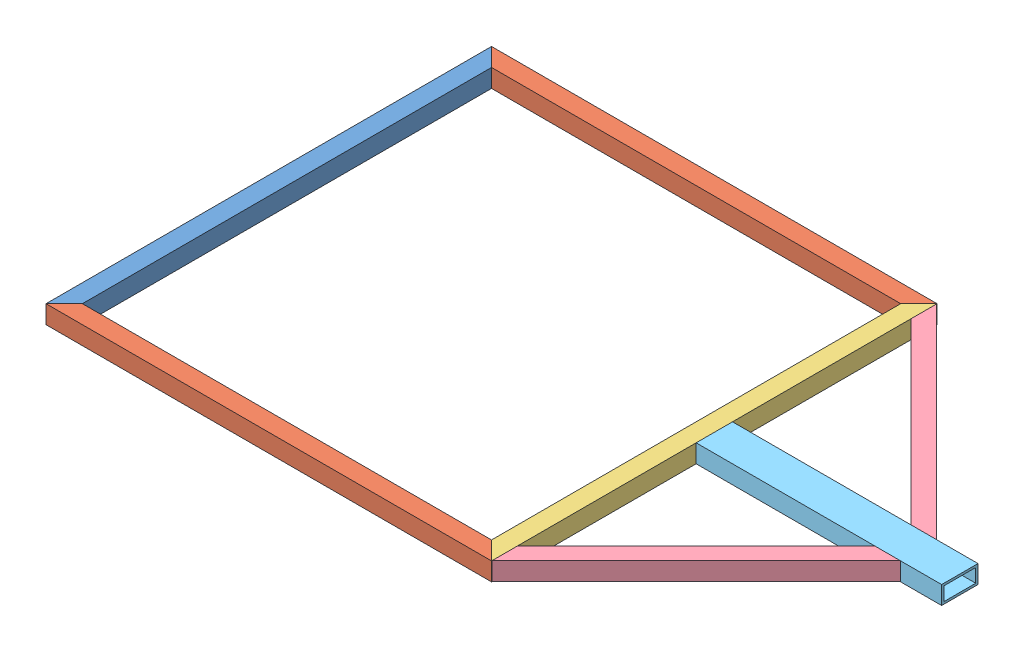
SolidWorks assembly chassis weldment top-1, configuration Default. Lengths in mm.
Overall size (965.2 25.4 622.3).
7 component instances, 5 part files, 0 mates.
Components (placement in the parent):
- frame member front-11-1: frame member front-11 [Default] at origin size (25.4 25.4 622.3)
- frame member side-11-1: frame member side-11 [Default] at (298.45 0 298.45) x (0 0 1) z (-1 0 0) size (25.4 25.4 622.3)
- frame member side-11-2: frame member side-11 [Default] at (298.45 0 -298.45) x (0 0 -1) z (-1 0 0) size (25.4 25.4 622.3)
- frame member crossbrace middle-11-1: frame member crossbrace middle-11 [Default] at (596.9 0 0) x (-1 0 0) z (0 0 1) size (25.4 25.4 622.3)
- frame member back angle-11-1: frame member back angle-11 [Default] at (743.1813 0 -158.9813) x (-0.707107 0 0.707107) z (-0.707107 0 -0.707107) size (25.4 25.4 403.23)
- frame member back angle-11-2: frame member back angle-11 [Default] at (743.1813 0 158.9813) x (-0.707107 0 -0.707107) z (-0.707107 0 0.707107) size (25.4 25.4 403.23)
- frame member back center-11-1: frame member back center-11 [Default] at (781.05 0 0) x (0 0 -1) z (1 0 0) size (50.8 25.4 342.9)
